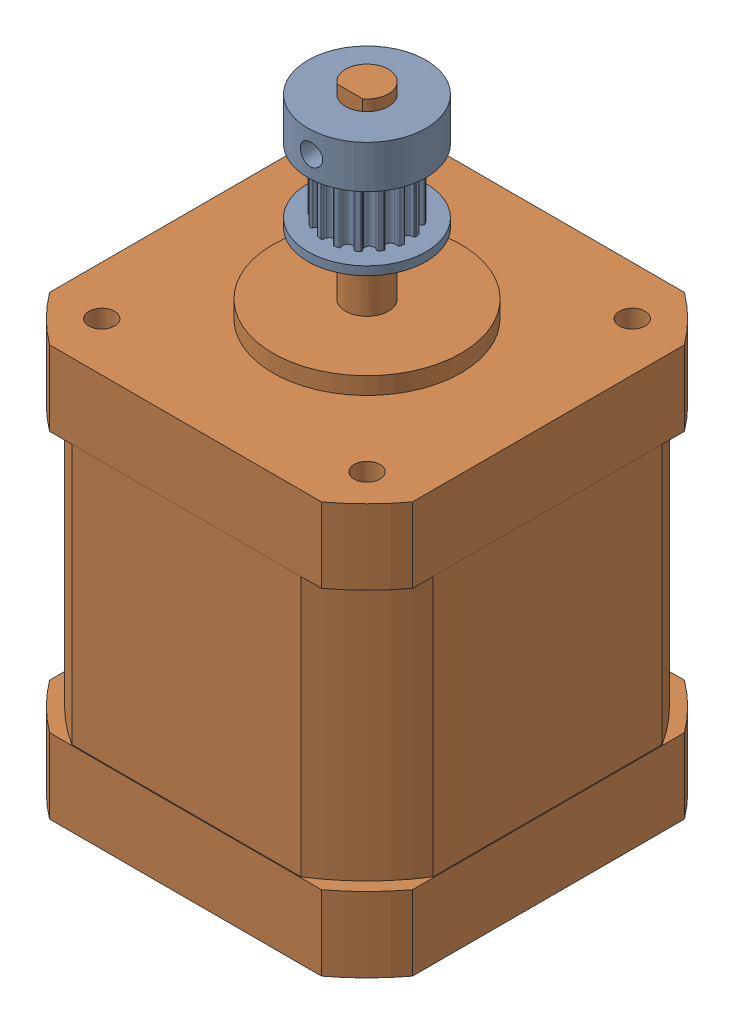
SolidWorks assembly xy_drive_stepper, configuration Default. Lengths in mm.
Overall size (42.42 72 42.42).
2 component instances, 2 part files, 0 mates.
Components (placement in the parent):
- drive_pulley_16t_gt2_6mm_belt-1: drive_pulley_16t_gt2_6mm_belt [Default] at (-27.429 406.7309 -32.1843) x (-0.044306 0 -0.999018) z (-0.999018 0 0.044306) size (13.8 13.5 13.8)
- 17HM19-2004S-1: 17HM19-2004S [Default] at (-27.429 384.0105 -32.1843) x (-1 0 0) z (0 1 0) size (42.42 42.42 72)
